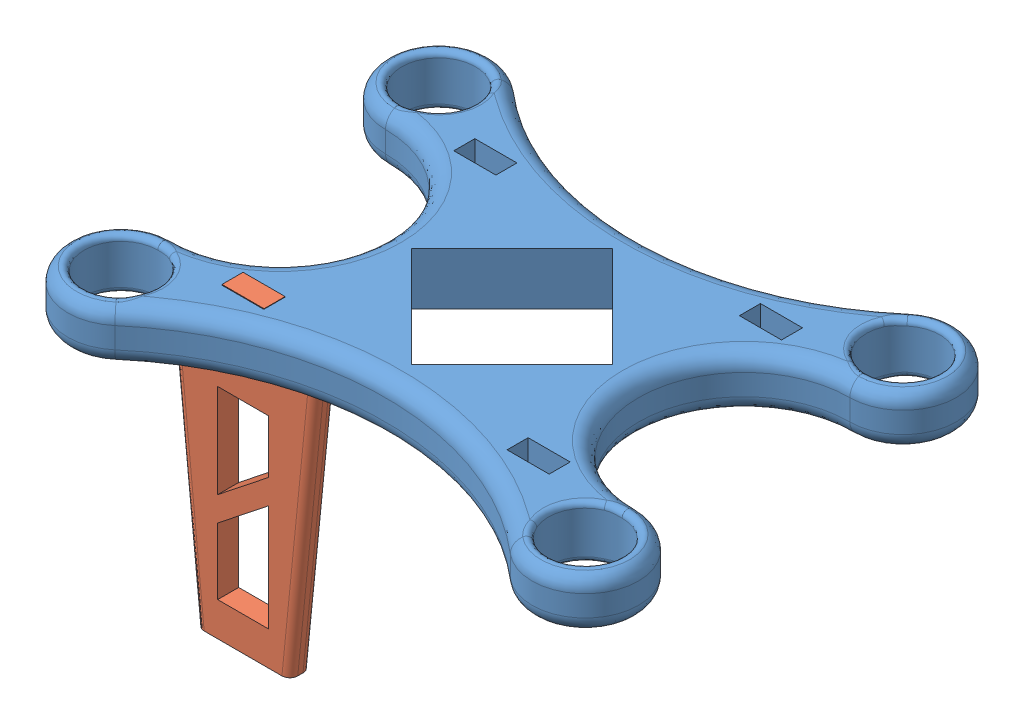
SolidWorks assembly Assem drone1, configuration Default. Lengths in mm.
Overall size (108.48 59.1 80.61).
2 component instances, 2 part files, 0 mates.
Components (placement in the parent):
- drone1-1: drone1 [Default] at origin size (108.48 10.71 80.61)
- leg-1: leg [Default] at (-20.3948 -37.2217 17.6203) size (27.59 58.76 4)
